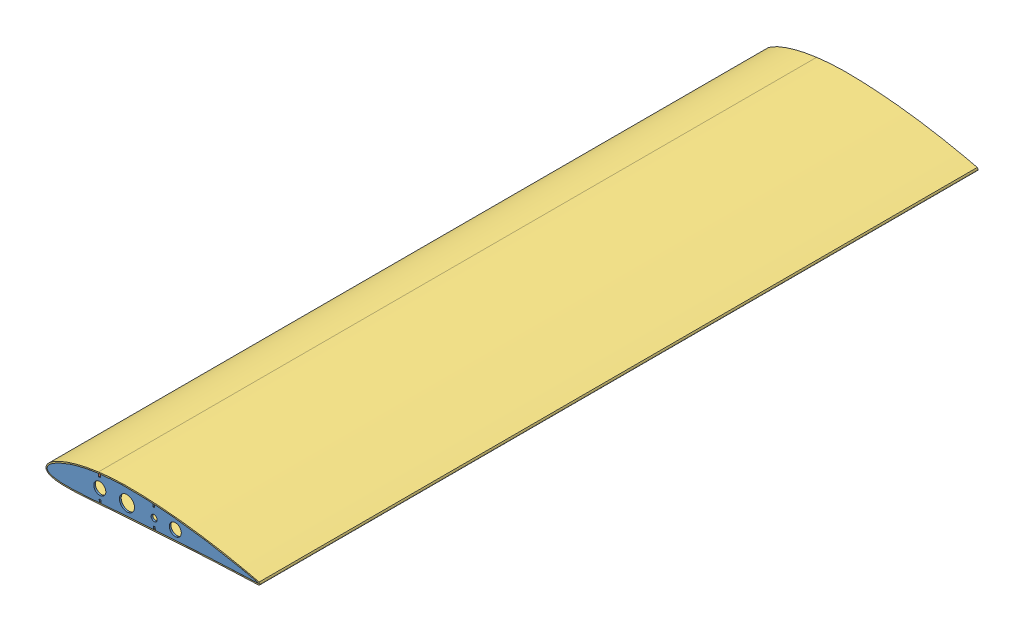
SolidWorks assembly DetailedWingAssembly, configuration Default. Lengths in mm.
Overall size (356.71 55.82 1199.92).
15 component instances, 3 part files, 38 mates.
Components (placement in the parent):
- polywoodRib350mm-1: polywoodRib350mm [Default] at (-118.7299 22.9602 -1140.1191) x (0.9996 0.028275 0) z (0 0 1) size (350.22 44.96 2.8)
- polywoodStringer-1: polywoodStringer [Default] at (-32.0822 54.3284 -548.5191) x (0 0 -1) z (0.9996 0.028275 0) size (202.8 16.16 2.8)
- polywoodRib350mm-2: polywoodRib350mm [Default] at (-118.7299 22.9602 -942.9191) x (0.9996 0.028275 0) z (0 0 1) size (350.22 44.96 2.8)
- polywoodRib350mm-3: polywoodRib350mm [Default] at (-118.7299 22.9602 -745.7191) x (0.9996 0.028275 0) z (0 0 1) size (350.22 44.96 2.8)
- polywoodRib350mm-4: polywoodRib350mm [Default] at (-118.7299 22.9602 -548.5191) x (0.9996 0.028275 0) z (0 0 1) size (350.22 44.96 2.8)
- polywoodRib350mm-5: polywoodRib350mm [Default] at (-118.7299 22.9602 -448.5191) x (0.9996 0.028275 0) z (0 0 1) size (350.22 44.96 2.8)
- polywoodRib350mm-6: polywoodRib350mm [Default] at (-118.7299 22.9602 -1337.3191) x (0.9996 0.028275 0) z (0 0 1) size (350.22 44.96 2.8)
- polywoodStringer-2: polywoodStringer [Default] at (-32.0822 54.3284 -745.7191) x (0 0 -1) z (0.9996 0.028275 0) size (202.8 16.16 2.8)
- polywoodStringer-3: polywoodStringer [Default] at (-32.0822 54.3284 -1337.3191) x (0 0 -1) z (0.9996 0.028275 0) size (202.8 16.16 2.8)
- polywoodStringer-4: polywoodStringer [Default] at (-32.0822 54.3284 -1140.1191) x (0 0 -1) z (0.9996 0.028275 0) size (202.8 16.16 2.8)
- polywoodStringer-5: polywoodStringer [Default] at (-32.0822 54.3284 -942.9191) x (0 0 -1) z (0.9996 0.028275 0) size (202.8 16.16 2.8)
- polywoodStringer-6: polywoodStringer [Default] at (-32.0822 54.3284 -1534.5191) x (0 0 -1) z (0.9996 0.028275 0) size (202.8 16.16 2.8)
- polywoodRib350mm-7: polywoodRib350mm [Default] at (-118.7299 22.9602 -1534.5191) x (0.9996 0.028275 0) z (0 0 1) size (350.22 44.96 2.8)
- polywoodRib350mm-8: polywoodRib350mm [Default] at (-118.7299 22.9602 -1634.5191) x (0.9996 0.028275 0) z (0 0 1) size (350.22 44.96 2.8)
- Деталь34-1: Деталь34 [Default] at origin size (356.71 54.06 1199.92)
Mates (geometry in assembly coordinates):
- Совпадение2: coincident anti-aligned: plane of polywoodStringer-1 through (-30.5719 50.4495 -547.1191) normal (0 0 -1); plane of polywoodRib350mm-4 through (-79.7254 48.0175 -547.1191) normal (0 0 1)
- Совпадение3: coincident anti-aligned: plane of polywoodStringer-1 through (-30.6511 53.2484 -547.1191) normal (0.028275 -0.9996 0); plane of polywoodRib350mm-4 through (-33.45 53.1692 -547.1191) normal (-0.028275 0.9996 0)
- Совпадение5: coincident anti-aligned: plane of polywoodStringer-1 through (-30.6828 54.3679 -548.5191) normal (0.9996 0.028275 0); plane of polywoodRib350mm-4 through (-30.7975 58.4237 -547.1191) normal (-0.9996 -0.028275 0)
- Совпадение6: coincident anti-aligned: plane of polywoodRib350mm-3 through (-30.7975 58.4237 -744.3191) normal (-0.9996 -0.028275 0); plane of polywoodStringer-2 through (-30.6828 54.3679 -745.7191) normal (0.9996 0.028275 0)
- Совпадение7: coincident anti-aligned: plane of polywoodRib350mm-3 through (-33.45 53.1692 -744.3191) normal (-0.028275 0.9996 0); plane of polywoodStringer-2 through (-30.6511 53.2484 -744.3191) normal (0.028275 -0.9996 0)
- Совпадение8: coincident anti-aligned: plane of polywoodRib350mm-3 through (-79.7254 48.0175 -747.1191) normal (0 0 -1); plane of polywoodStringer-2 through (-30.5719 50.4495 -747.1191) normal (0 0 1)
- Совпадение10: coincident anti-aligned: plane of polywoodStringer-1 through (-30.7936 58.2864 -644.3191) normal (0 0 -1); plane of polywoodStringer-2 through (-30.6828 54.3679 -644.3191) normal (0 0 1)
- Совпадение11: coincident aligned: plane of polywoodStringer-1 through (-33.4816 54.2888 -548.5191) normal (-0.9996 -0.028275 0); plane of polywoodStringer-2 through (-33.4816 54.2888 -745.7191) normal (-0.9996 -0.028275 0)
- Совпадение12: coincident anti-aligned: plane of polywoodRib350mm-2 through (-30.7975 58.4237 -941.5191) normal (-0.9996 -0.028275 0); plane of polywoodStringer-5 through (-30.6828 54.3679 -942.9191) normal (0.9996 0.028275 0)
- Совпадение13: coincident anti-aligned: plane of polywoodRib350mm-2 through (-79.7254 48.0175 -944.3191) normal (0 0 -1); plane of polywoodStringer-5 through (-30.5719 50.4495 -944.3191) normal (0 0 1)
- Совпадение14: coincident anti-aligned: plane of polywoodRib350mm-2 through (-33.45 53.1692 -941.5191) normal (-0.028275 0.9996 0); plane of polywoodStringer-5 through (-30.6511 53.2484 -941.5191) normal (0.028275 -0.9996 0)
- Совпадение15: coincident anti-aligned: plane of polywoodStringer-2 through (-30.7936 58.2864 -841.5191) normal (0 0 -1); plane of polywoodStringer-5 through (-30.6828 54.3679 -841.5191) normal (0 0 1)
- Совпадение16: coincident aligned: plane of polywoodStringer-2 through (-33.4816 54.2888 -745.7191) normal (-0.9996 -0.028275 0); plane of polywoodStringer-5 through (-33.4816 54.2888 -942.9191) normal (-0.9996 -0.028275 0)
- Совпадение17: coincident anti-aligned: plane of polywoodRib350mm-1 through (-33.5884 58.0639 -1138.7191) normal (0.9996 0.028275 0); plane of polywoodStringer-4 through (-33.4816 54.2888 -1140.1191) normal (-0.9996 -0.028275 0)
- Совпадение18: coincident anti-aligned: plane of polywoodRib350mm-1 through (-79.7254 48.0175 -1141.5191) normal (0 0 -1); plane of polywoodStringer-4 through (-30.5719 50.4495 -1141.5191) normal (0 0 1)
- Совпадение19: coincident anti-aligned: plane of polywoodRib350mm-1 through (-33.45 53.1692 -1138.7191) normal (-0.028275 0.9996 0); plane of polywoodStringer-4 through (-30.6511 53.2484 -1138.7191) normal (0.028275 -0.9996 0)
- Совпадение20: coincident aligned: plane of polywoodStringer-4 through (-33.4816 54.2888 -1140.1191) normal (-0.9996 -0.028275 0); plane of polywoodStringer-5 through (-33.4816 54.2888 -942.9191) normal (-0.9996 -0.028275 0)
- Совпадение21: coincident anti-aligned: plane of polywoodStringer-4 through (-30.6828 54.3679 -1038.7191) normal (0 0 1); plane of polywoodStringer-5 through (-30.7936 58.2864 -1038.7191) normal (0 0 -1)
- Совпадение22: coincident anti-aligned: plane of polywoodRib350mm-6 through (-33.5884 58.0639 -1335.9191) normal (0.9996 0.028275 0); plane of polywoodStringer-3 through (-33.4816 54.2888 -1337.3191) normal (-0.9996 -0.028275 0)
- Совпадение23: coincident anti-aligned: plane of polywoodRib350mm-6 through (-79.7254 48.0175 -1338.7191) normal (0 0 -1); plane of polywoodStringer-3 through (-30.5719 50.4495 -1338.7191) normal (0 0 1)
- Совпадение24: coincident anti-aligned: plane of polywoodRib350mm-6 through (-33.45 53.1692 -1335.9191) normal (-0.028275 0.9996 0); plane of polywoodStringer-3 through (-30.6511 53.2484 -1335.9191) normal (0.028275 -0.9996 0)
- Совпадение25: coincident aligned: plane of polywoodStringer-3 through (-33.4816 54.2888 -1337.3191) normal (-0.9996 -0.028275 0); plane of polywoodStringer-4 through (-33.4816 54.2888 -1140.1191) normal (-0.9996 -0.028275 0)
- Совпадение26: coincident anti-aligned: plane of polywoodStringer-3 through (-30.6828 54.3679 -1241.5191) normal (0 0 1); plane of polywoodStringer-4 through (-30.5719 50.4495 -1241.5191) normal (0 0 -1)
- Совпадение27: coincident aligned: plane of polywoodStringer-1 through (-30.6828 54.3679 -447.1191) normal (0 0 1); plane of polywoodRib350mm-5 through (-79.7254 48.0175 -447.1191) normal (0 0 1)
- Совпадение28: coincident anti-aligned: plane of polywoodStringer-1 through (-33.4816 54.2888 -548.5191) normal (-0.9996 -0.028275 0); plane of polywoodRib350mm-5 through (-33.5884 58.0639 -447.1191) normal (0.9996 0.028275 0)
- Совпадение29: coincident aligned: plane of polywoodStringer-3 through (-33.4816 54.2888 -1337.3191) normal (-0.9996 -0.028275 0); plane of polywoodStringer-6 through (-33.4816 54.2888 -1534.5191) normal (-0.9996 -0.028275 0)
- Совпадение30: coincident anti-aligned: plane of polywoodStringer-3 through (-30.5719 50.4495 -1438.7191) normal (0 0 -1); plane of polywoodStringer-6 through (-30.6828 54.3679 -1438.7191) normal (0 0 1)
- Совпадение31: coincident anti-aligned: plane of polywoodStringer-6 through (-30.5719 50.4495 -1535.9191) normal (0 0 1); plane of polywoodRib350mm-7 through (-79.7254 48.0175 -1535.9191) normal (0 0 -1)
- Совпадение32: coincident anti-aligned: plane of polywoodStringer-6 through (-30.6511 53.2484 -1533.1191) normal (0.028275 -0.9996 0); plane of polywoodRib350mm-7 through (-33.45 53.1692 -1533.1191) normal (-0.028275 0.9996 0)
- Концентричный11: concentric aligned: cylinder of polywoodRib350mm-7 through (-31.6051 37.4607 -1533.1191) axis (0 0 -1) radius 10; cylinder of polywoodRib350mm-8 through (-31.6051 37.4607 -1633.1191) axis (0 0 -1) radius 10
- Совпадение47: coincident aligned: plane of polywoodStringer-6 through (-30.5719 50.4495 -1635.9191) normal (0 0 -1); plane of polywoodRib350mm-8 through (-79.7254 48.0175 -1635.9191) normal (0 0 -1)
- Совпадение48: coincident anti-aligned: plane of polywoodStringer-6 through (-30.6828 54.3679 -1534.5191) normal (0.9996 0.028275 0); plane of polywoodRib350mm-8 through (-30.7975 58.4237 -1633.1191) normal (-0.9996 -0.028275 0)
- Концентричный12: concentric aligned: cylinder of polywoodRib350mm-6 through (-31.6051 37.4607 -1335.9191) axis (0 0 -1) radius 10; cylinder of polywoodRib350mm-7 through (-31.6051 37.4607 -1533.1191) axis (0 0 -1) radius 10
- Концентричный13: concentric aligned: cylinder of polywoodRib350mm-1 through (-31.6051 37.4607 -1138.7191) axis (0 0 -1) radius 10; cylinder of polywoodRib350mm-6 through (-31.6051 37.4607 -1335.9191) axis (0 0 -1) radius 10
- Концентричный14: concentric aligned: cylinder of polywoodRib350mm-1 through (-31.6051 37.4607 -1138.7191) axis (0 0 -1) radius 10; cylinder of polywoodRib350mm-2 through (-31.6051 37.4607 -941.5191) axis (0 0 -1) radius 10
- Концентричный15: concentric aligned: cylinder of polywoodRib350mm-2 through (-31.6051 37.4607 -941.5191) axis (0 0 -1) radius 10; cylinder of polywoodRib350mm-3 through (-31.6051 37.4607 -744.3191) axis (0 0 -1) radius 10
- Концентричный16: concentric aligned: cylinder of polywoodRib350mm-3 through (-31.6051 37.4607 -744.3191) axis (0 0 -1) radius 10; cylinder of polywoodRib350mm-4 through (-31.6051 37.4607 -547.1191) axis (0 0 -1) radius 10
- Концентричный17: concentric aligned: cylinder of polywoodRib350mm-4 through (-31.6051 37.4607 -547.1191) axis (0 0 -1) radius 10; cylinder of polywoodRib350mm-5 through (-31.6051 37.4607 -447.1191) axis (0 0 -1) radius 10
